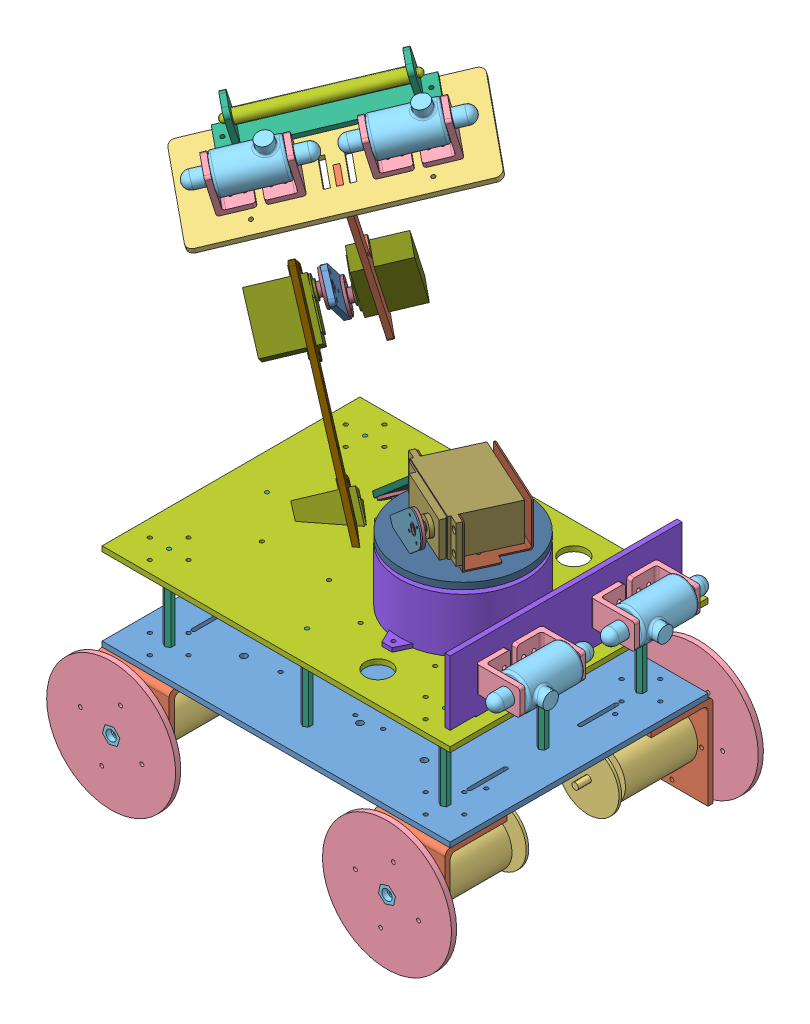
SolidWorks assembly robot_config5 - Copy (2), configuration Default. Lengths in mm.
Overall size (396.29 402.14 292.25).
62 component instances, 26 part files, 158 mates.
Components (placement in the parent):
- base_odroid_down_fix-1: base_odroid_down_fix [Default] at (39.4639 122.941 229.7749) x (1 0 0) z (0 -1 0) size (270 200 4)
- link_motor_1_port-1: link_motor_1_port [Default] at (221.3654 106.3394 287.3354) x (0 0 -1) z (1 0 0) size (48 72 56)
- motor_dc_NISCA-1: motor_dc_NISCA [Default] at (244.2642 39.7289 313.6416) x (0 -1 0) z (0 0 -1) size (54 48 92)
- roda_shaft-1: roda_shaft [Default] at (185.8398 121.6563 330.6416) x (-0.980223 0.197896 0) z (0 0 1) size (100 100 4)
- shaft_adapter_5mm-1: shaft_adapter_5mm [Default] at (248.7954 72.9583 317.6416) x (0.980223 -0.197896 0) z (0 0 1) size (12 13.86 17)
- link_motor_1_port-2: link_motor_1_port [Default] at (221.3654 106.3394 139.9479) x (0 0 1) z (-1 0 0) size (48 72 56)
- motor_dc_NISCA-2: motor_dc_NISCA [Default] at (198.4666 39.7289 113.6416) x (0 -1 0) z (0 0 1) size (54 48 92)
- shaft_adapter_5mm-3: shaft_adapter_5mm [Default] at (200.8263 105.1818 109.6416) x (-0.553843 0.832621 0) z (0 0 -1) size (12 13.86 17)
- roda_shaft-2: roda_shaft [Default] at (229.4077 32.7567 96.6416) x (-0.44415 -0.895953 0) z (0 0 -1) size (100 100 4)
- link_motor_1_port-5: link_motor_1_port [Default] at (7.3654 106.3394 287.3354) x (0 0 -1) z (1 0 0) size (48 72 56)
- motor_dc_NISCA-5: motor_dc_NISCA [Default] at (-15.5334 128.1531 313.6416) x (0 1 0) z (0 0 -1) size (54 48 92)
- roda_shaft-5: roda_shaft [Default] at (-41.8024 67.5996 334.6416) x (-0.956744 0.29093 0) z (0 0 -1) size (100 100 4)
- shaft_adapter_5mm-6: shaft_adapter_5mm [Default] at (33.6165 70.3799 317.6416) x (0.956744 -0.29093 0) z (0 0 1) size (12 13.86 17)
- link_motor_1_port-6: link_motor_1_port [Default] at (7.3654 106.3394 139.9479) x (0 0 1) z (-1 0 0) size (48 72 56)
- motor_dc_NISCA-6: motor_dc_NISCA [Default] at (-15.5334 39.7289 113.6416) x (0 -1 0) z (0 0 1) size (54 48 92)
- roda_shaft-6: roda_shaft [Default] at (45.258 48.6046 96.6416) x (0.202799 -0.97922 0) z (0 0 -1) size (100 100 4)
- shaft_adapter_5mm-7: shaft_adapter_5mm [Default] at (36.6325 79.8838 109.6416) x (0.949429 -0.313981 0) z (0 0 -1) size (12 13.86 17)
- spacer_6cm-2: spacer_6cm [Default] at (221.7099 182.941 288.7798) x (0.5 0 -0.866025) z (0 -1 0) size (6 6.93 68)
- spacer_6cm-3: spacer_6cm [Default] at (114.7099 182.941 288.7798) x (0.5 0 -0.866025) z (0 -1 0) size (6 6.93 68)
- spacer_6cm-4: spacer_6cm [Default] at (7.7099 182.941 288.7798) x (0.5 0 -0.866025) z (0 -1 0) size (6 6.93 68)
- spacer_6cm-5: spacer_6cm [Default] at (221.7099 182.941 212.7798) x (0.5 0 -0.866025) z (0 -1 0) size (6 6.93 68)
- spacer_6cm-7: spacer_6cm [Default] at (7.7099 182.941 212.7798) x (0.5 0 -0.866025) z (0 -1 0) size (6 6.93 68)
- spacer_6cm-8: spacer_6cm [Default] at (221.7099 182.941 136.7798) x (0.5 0 -0.866025) z (0 -1 0) size (6 6.93 68)
- spacer_6cm-9: spacer_6cm [Default] at (114.7099 182.941 136.7798) x (0.5 0 -0.866025) z (0 -1 0) size (6 6.93 68)
- spacer_6cm-10: spacer_6cm [Default] at (7.7099 182.941 136.7798) x (0.5 0 -0.866025) z (0 -1 0) size (6 6.93 68)
- base_odroid_up_fix-1: base_odroid_up_fix [Default] at (186.1287 186.941 197.5083) x (-1 0 0) z (0 -1 0) size (270 200 4)
- base_arm-1: base_arm [Default] at (159.3654 194.0898 219.4289) x (0 0 1) z (-1 0 0) size (118.01 42 118.01)
- servo_hs422-1: servo_hs422 [Default] at (169.6524 210.6756 203.7356) x (0 0 1) z (-1 0 0) size (19.81 42.14 58.23)
- link1_arm-1: link1_arm [Default] at (135.1247 232.0663 202.5671) x (-0.909573 0 -0.415545) z (0 1 0) size (98 98 12)
- bracket_servo_hs755-1: bracket_servo_hs755 [Default] at (176.7251 266.4802 264.6833) x (-0.415545 0 0.909573) z (-0.909573 0 -0.415545) size (44 34 74)
- servo_hs755-1: servo_hs755 [Default] at (178.9415 211.9363 195.0997) x (0 -1 0) z (-0.415545 0 0.909573) size (29 74 56.99)
- servo_horn_general-1: servo_horn_general [Default] at (190.0175 289.5121 265.0144) x (0.696773 0.642788 0.318326) z (0.415545 0 -0.909573) size (24 24 6)
- link2_ubracket-2: link2_ubracket [Default] at (158.0154 222.8169 200.5977) x (0.415545 0 -0.909573) z (-0.584662 0.766044 -0.267107) size (66 59 24)
- link2_fix-2: link2_fix [Default] at (114.6727 188.4592 181.7629) x (0.584662 -0.766044 0.267107) z (-0.415545 0 0.909573) size (45.14 89 24)
- servo_horn_general-2: servo_horn_general [Default] at (103.8923 228.8235 186.5401) x (0.696773 0.642788 0.318326) z (0.584662 -0.766044 0.267107) size (24 24 6)
- servo_hs645-2: servo_hs645 [Default] at (126.0021 193.6332 203.2764) x (0.504037 0.60098 0.620298) z (-0.584662 0.766044 -0.267107) size (53.34 19.56 42.35)
- bracket_servo_645-2: bracket_servo_645 [Default] at (74.1941 209.6602 189.4229) x (-0.584662 0.766044 -0.267107) z (-0.504037 -0.60098 -0.620298) size (34 24 57)
- servo_horn_general-3: servo_horn_general [Default] at (55.5106 142.3644 163.5271) x (-0.33554 -0.778769 -0.53003) z (-0.635702 -0.228033 0.737485) size (24 24 6)
- servo_hs645-3: servo_hs645 [Default] at (65.2626 126.9078 227.2968) x (0.612579 -0.730355 0.302206) z (0.635702 0.228033 -0.737485) size (53.34 19.56 42.35)
- link4_fix-1: link4_fix [Default] at (-61.5231 313.2532 136.8813) x (-0.612579 0.730355 -0.302206) z (0.635702 0.228033 -0.737485) size (176.25 35 4)
- servo_hs645-4: servo_hs645 [Default] at (-62.0861 309.963 174.1253) x (-0.612579 0.730355 -0.302206) z (0.635702 0.228033 -0.737485) size (53.34 19.56 42.35)
- link5_fix-1: link5_fix [Default] at (-52.3441 298.5328 118.8456) x (-0.612579 0.730355 -0.302206) z (0.635702 0.228033 -0.737485) size (24 90 4)
- servo_horn_general-4: servo_horn_general [Default] at (10.0609 307.9733 175.5569) x (0.469713 0.643881 0.603976) z (-0.635702 -0.228033 0.737485) size (24 24 6)
- servo_horn_general-5: servo_horn_general [Default] at (-62.2618 206.2599 76.3417) x (-0.469713 -0.643881 -0.603976) z (0.635702 0.228033 -0.737485) size (24 24 6)
- servo_hs645-5: servo_hs645 [Default] at (-5.9799 205.0814 64.3486) x (-0.048645 -0.941639 -0.33309) z (-0.635702 -0.228033 0.737485) size (53.34 19.56 42.35)
- link6_eff-1: link6_eff [Default] at (-35.7215 211.1303 71.6661) x (-0.048645 -0.941639 -0.33309) z (-0.635702 -0.228033 0.737485) size (140.63 35 4)
- base_link_effector_fix-2: base_link_effector_fix [Default] at (-1.9069 349.6133 142.6833) x (-0.635702 -0.228033 0.737485) z (0.048645 0.941639 0.33309) size (180 80 4)
- base_webcam_fix1-2: base_webcam_fix1 [Default] at (41.365 368.6316 94.6083) x (-0.635702 -0.228033 0.737485) z (-0.7704 0.247621 -0.587509) size (23 34 20)
- base_webcam_fix1-3: base_webcam_fix1 [Default] at (-6.4638 361.9543 120.4699) x (0.635702 0.228033 -0.737485) z (0.7704 -0.247621 0.587509) size (23 34 20)
- base_webcam_fix1-4: base_webcam_fix1 [Default] at (-15.2125 348.3366 160.2445) x (-0.635702 -0.228033 0.737485) z (-0.7704 0.247621 -0.587509) size (23 34 20)
- base_webcam_fix1-5: base_webcam_fix1 [Default] at (-63.0413 341.6594 186.106) x (0.635702 0.228033 -0.737485) z (0.7704 -0.247621 0.587509) size (23 34 20)
- webcam_sturdy-3: webcam_sturdy [Default] at (2.21 382.0065 134.5684) x (-0.635702 -0.228033 0.737485) z (0.048645 0.941639 0.33309) size (79 27 33.5)
- webcam_sturdy-4: webcam_sturdy [Default] at (-54.3675 361.7116 200.2045) x (-0.635702 -0.228033 0.737485) z (0.048645 0.941639 0.33309) size (79 27 33.5)
- base_GM-1: base_GM [Default] at (-59.9622 361.6513 153.8993) x (-0.635702 -0.228033 0.737485) z (-0.7704 0.247621 -0.587509) size (128 34 20)
- tabung_GM-1: tabung_GM [Default] at (-109.1173 363.7111 126.0884) x (-0.762485 0.036461 -0.645978) z (0.635702 0.228033 -0.737485) size (10 10 116)
- base_webam_base-2: base_webam_base [Default] at (235.3654 219.0582 216.3423) x (0 0 -1) z (1 0 0) size (180 55 4)
- base_webcam_fix1-7: base_webcam_fix1 [Default] at (239.3654 202.941 143.6416) x (0 0 1) z (0 1 0) size (23 34 20)
- base_webcam_fix1-8: base_webcam_fix1 [Default] at (239.3654 222.941 194.6416) x (0 0 -1) z (0 -1 0) size (23 34 20)
- base_webcam_fix1-9: base_webcam_fix1 [Default] at (239.3654 222.941 283.6416) x (0 0 -1) z (0 -1 0) size (23 34 20)
- base_webcam_fix1-10: base_webcam_fix1 [Default] at (239.3654 202.941 232.6416) x (0 0 1) z (0 1 0) size (23 34 20)
- webcam_sturdy-5: webcam_sturdy [Default] at (263.3654 212.941 143.3307) x (0 0 -1) z (1 0 0) size (79 27 33.5)
- webcam_sturdy-6: webcam_sturdy [Default] at (263.3654 212.941 232.3307) x (0 0 -1) z (1 0 0) size (79 27 33.5)
Mates (geometry in assembly coordinates):
- Coincident1: coincident anti-aligned: plane of link_motor_1_port-1 through (193.3654 46.941 313.6416) normal (0 0 -1); plane of motor_dc_NISCA-1 through (221.3654 83.941 313.6416) normal (0 0 1)
- Concentric1: concentric aligned: cylinder of link_motor_1_port-1 through (221.3654 83.941 317.6416) axis (0 0 -1) radius 9.5; cylinder of motor_dc_NISCA-1 through (221.3654 83.941 317.6416) axis (0 0 -1) radius 9
- Concentric2: concentric anti-aligned: cylinder of link_motor_1_port-1 through (221.3654 106.941 317.6416) axis (0 0 -1) radius 1.5; cylinder of motor_dc_NISCA-1 through (221.3654 106.941 311.6416) axis (0 0 1) radius 1.5
- Coincident2: coincident anti-aligned: plane of motor_dc_NISCA-1 through (244.2642 39.7289 317.6416) normal (0 0 1); plane of shaft_adapter_5mm-1 through (221.3654 83.941 317.6416) normal (0 0 -1)
- Concentric4: concentric aligned: cylinder of motor_dc_NISCA-1 through (221.3654 83.941 330.6416) axis (0 0 -1) radius 2.5; cylinder of shaft_adapter_5mm-1 through (221.3654 83.941 330.6416) axis (0 0 -1) radius 2.5
- Coincident3: coincident anti-aligned: plane of roda_shaft-1 through (222.7365 90.7322 322.6416) normal (0.318728 -0.947846 0); plane of shaft_adapter_5mm-1 through (222.7365 90.7322 334.6416) normal (-0.318728 0.947846 0)
- Coincident4: coincident aligned: plane of roda_shaft-1 through (221.3654 83.941 334.6416) normal (0 0 1); plane of shaft_adapter_5mm-1 through (248.7954 72.9583 334.6416) normal (0 0 1)
- Coincident7: coincident anti-aligned: plane of roda_shaft-1 through (214.7985 81.7328 322.6416) normal (0.661495 0.74995 0); plane of shaft_adapter_5mm-1 through (214.7985 81.7328 334.6416) normal (-0.661495 -0.74995 0)
- Coincident8: coincident anti-aligned: plane of link_motor_1_port-2 through (249.3654 46.941 113.6416) normal (0 0 1); plane of motor_dc_NISCA-2 through (221.3654 83.941 113.6416) normal (0 0 -1)
- Concentric5: concentric aligned: cylinder of link_motor_1_port-2 through (221.3654 83.941 109.6416) axis (0 0 1) radius 9.5; cylinder of motor_dc_NISCA-2 through (221.3654 83.941 109.6416) axis (0 0 1) radius 9
- Concentric7: concentric anti-aligned: cylinder of link_motor_1_port-2 through (221.3654 106.941 109.6416) axis (0 0 1) radius 1.5; cylinder of motor_dc_NISCA-2 through (221.3654 106.941 115.6416) axis (0 0 -1) radius 1.5
- Coincident9: coincident anti-aligned: plane of base_odroid_down_fix-1 through (39.4639 118.941 229.7749) normal (0 -1 0); plane of link_motor_1_port-1 through (193.3654 118.941 269.6416) normal (0 1 0)
- Concentric8: concentric anti-aligned: cylinder of base_odroid_down_fix-1 through (206.3654 118.941 289.6416) axis (0 1 0) radius 1.5; cylinder of link_motor_1_port-1 through (206.3654 118.941 289.6416) axis (0 -1 0) radius 1.5
- Concentric9: concentric anti-aligned: cylinder of base_odroid_down_fix-1 through (236.3654 118.941 289.6416) axis (0 1 0) radius 1.5; cylinder of link_motor_1_port-1 through (236.3654 118.941 289.6416) axis (0 -1 0) radius 1.5
- Coincident11: coincident aligned: plane of shaft_adapter_5mm-3 through (200.8263 105.1818 92.6416) normal (0 0 -1); plane of roda_shaft-2 through (221.3654 83.941 92.6416) normal (0 0 -1)
- Coincident12: coincident anti-aligned: plane of shaft_adapter_5mm-3 through (220.9266 90.8553 92.6416) normal (0.44415 0.895953 0); plane of roda_shaft-2 through (220.9266 90.8553 104.6416) normal (-0.44415 -0.895953 0)
- Coincident13: coincident anti-aligned: plane of shaft_adapter_5mm-3 through (215.5968 80.1039 92.6416) normal (-0.997993 -0.063332 0); plane of roda_shaft-2 through (215.5968 80.1039 104.6416) normal (0.997993 0.063332 0)
- Coincident14: coincident anti-aligned: plane of motor_dc_NISCA-2 through (198.4666 39.7289 109.6416) normal (0 0 -1); plane of shaft_adapter_5mm-3 through (221.3654 83.941 109.6416) normal (0 0 1)
- Concentric10: concentric aligned: cylinder of motor_dc_NISCA-2 through (221.3654 83.941 96.6416) axis (0 0 1) radius 2.5; cylinder of shaft_adapter_5mm-3 through (221.3654 83.941 96.6416) axis (0 0 1) radius 2.5
- Coincident15: coincident anti-aligned: plane of base_odroid_down_fix-1 through (39.4639 118.941 229.7749) normal (0 -1 0); plane of link_motor_1_port-2 through (249.3654 118.941 157.6416) normal (0 1 0)
- Concentric11: concentric anti-aligned: cylinder of base_odroid_down_fix-1 through (206.3654 118.941 137.6416) axis (0 1 0) radius 1.5; cylinder of link_motor_1_port-2 through (206.3654 118.941 137.6416) axis (0 -1 0) radius 1.5
- Concentric12: concentric anti-aligned: cylinder of base_odroid_down_fix-1 through (236.3654 118.941 137.6416) axis (0 1 0) radius 1.5; cylinder of link_motor_1_port-2 through (236.3654 118.941 137.6416) axis (0 -1 0) radius 1.5
- Coincident16: coincident anti-aligned: plane of link_motor_1_port-5 through (-20.6346 46.941 313.6416) normal (0 0 -1); plane of motor_dc_NISCA-5 through (7.3654 83.941 313.6416) normal (0 0 1)
- Concentric13: concentric aligned: cylinder of link_motor_1_port-5 through (7.3654 83.941 317.6416) axis (0 0 -1) radius 9.5; cylinder of motor_dc_NISCA-5 through (7.3654 83.941 317.6416) axis (0 0 -1) radius 9
- Concentric14: concentric anti-aligned: cylinder of link_motor_1_port-5 through (7.3654 106.941 317.6416) axis (0 0 -1) radius 1.5; cylinder of motor_dc_NISCA-5 through (7.3654 106.941 311.6416) axis (0 0 1) radius 1.5
- Concentric16: concentric aligned: cylinder of motor_dc_NISCA-5 through (7.3654 83.941 330.6416) axis (0 0 -1) radius 2.5; cylinder of shaft_adapter_5mm-6 through (7.3654 83.941 330.6416) axis (0 0 -1) radius 2.5
- Coincident17: coincident anti-aligned: plane of motor_dc_NISCA-5 through (-15.5334 128.1531 317.6416) normal (0 0 1); plane of shaft_adapter_5mm-6 through (7.3654 83.941 317.6416) normal (0 0 -1)
- Coincident18: coincident anti-aligned: plane of roda_shaft-5 through (2.6327 89.0009 342.6416) normal (0.226419 -0.97403 0); plane of shaft_adapter_5mm-6 through (9.381 90.5695 334.6416) normal (-0.226419 0.97403 0)
- Coincident19: coincident aligned: plane of roda_shaft-5 through (7.3654 83.941 334.6416) normal (0 0 1); plane of shaft_adapter_5mm-6 through (33.6165 70.3799 334.6416) normal (0 0 1)
- Coincident20: coincident anti-aligned: plane of roda_shaft-5 through (14.1137 85.5097 342.6416) normal (-0.956744 0.29093 0); plane of shaft_adapter_5mm-6 through (12.098 78.8812 334.6416) normal (0.956744 -0.29093 0)
- Coincident21: coincident anti-aligned: plane of base_odroid_down_fix-1 through (39.4639 118.941 229.7749) normal (0 -1 0); plane of link_motor_1_port-5 through (-20.6346 118.941 269.6416) normal (0 1 0)
- Concentric17: concentric anti-aligned: cylinder of base_odroid_down_fix-1 through (-7.6346 118.941 289.6416) axis (0 1 0) radius 1.5; cylinder of link_motor_1_port-5 through (-7.6346 118.941 289.6416) axis (0 -1 0) radius 1.5
- Concentric18: concentric anti-aligned: cylinder of base_odroid_down_fix-1 through (22.3654 118.941 289.6416) axis (0 1 0) radius 1.5; cylinder of link_motor_1_port-5 through (22.3654 118.941 289.6416) axis (0 -1 0) radius 1.5
- Coincident22: coincident anti-aligned: plane of link_motor_1_port-6 through (35.3654 46.941 113.6416) normal (0 0 1); plane of motor_dc_NISCA-6 through (7.3654 83.941 113.6416) normal (0 0 -1)
- Concentric19: concentric aligned: cylinder of link_motor_1_port-6 through (7.3654 83.941 109.6416) axis (0 0 1) radius 9.5; cylinder of motor_dc_NISCA-6 through (7.3654 83.941 109.6416) axis (0 0 1) radius 9
- Concentric20: concentric anti-aligned: cylinder of link_motor_1_port-6 through (7.3654 106.941 109.6416) axis (0 0 1) radius 1.5; cylinder of motor_dc_NISCA-6 through (7.3654 106.941 115.6416) axis (0 0 -1) radius 1.5
- Concentric21: concentric aligned: cylinder of motor_dc_NISCA-6 through (7.3654 83.941 96.6416) axis (0 0 1) radius 2.5; cylinder of shaft_adapter_5mm-7 through (7.3654 83.941 96.6416) axis (0 0 1) radius 2.5
- Coincident23: coincident anti-aligned: plane of motor_dc_NISCA-6 through (-15.5334 39.7289 109.6416) normal (0 0 -1); plane of shaft_adapter_5mm-7 through (7.3654 83.941 109.6416) normal (0 0 1)
- Coincident24: coincident aligned: plane of roda_shaft-6 through (7.3654 83.941 92.6416) normal (0 0 -1); plane of shaft_adapter_5mm-7 through (36.6325 79.8838 92.6416) normal (0 0 -1)
- Coincident25: coincident anti-aligned: plane of roda_shaft-6 through (2.7565 89.1138 104.6416) normal (0.202799 -0.97922 0); plane of shaft_adapter_5mm-7 through (2.7565 89.1138 92.6416) normal (-0.202799 0.97922 0)
- Coincident26: coincident anti-aligned: plane of roda_shaft-6 through (5.1901 77.3632 104.6416) normal (0.74663 0.665239 0); plane of shaft_adapter_5mm-7 through (5.1901 77.3632 92.6416) normal (-0.74663 -0.665239 0)
- Coincident27: coincident anti-aligned: plane of base_odroid_down_fix-1 through (39.4639 118.941 229.7749) normal (0 -1 0); plane of link_motor_1_port-6 through (35.3654 118.941 157.6416) normal (0 1 0)
- Concentric22: concentric anti-aligned: cylinder of base_odroid_down_fix-1 through (-7.6346 118.941 137.6416) axis (0 1 0) radius 1.5; cylinder of link_motor_1_port-6 through (-7.6346 118.941 137.6416) axis (0 -1 0) radius 1.5
- Concentric23: concentric anti-aligned: cylinder of base_odroid_down_fix-1 through (22.3654 118.941 137.6416) axis (0 1 0) radius 1.5; cylinder of link_motor_1_port-6 through (22.3654 118.941 137.6416) axis (0 -1 0) radius 1.5
- Concentric24: concentric aligned: cylinder of base_odroid_down_fix-1 through (221.3654 118.941 289.6416) axis (0 1 0) radius 1.5; cylinder of spacer_6cm-2 through (221.3654 118.941 289.6416) axis (0 1 0) radius 1.5
- Coincident28: coincident anti-aligned: plane of base_odroid_down_fix-1 through (39.4639 122.941 229.7749) normal (0 1 0); plane of spacer_6cm-2 through (221.7099 122.941 288.7798) normal (0 -1 0)
- Parallel2: parallel aligned: plane of base_odroid_down_fix-1 through (249.3654 118.941 229.7749) normal (1 0 0); plane of spacer_6cm-2 through (224.3654 122.941 287.9096) normal (1 0 0)
- Concentric25: concentric anti-aligned: cylinder of spacer_6cm-2 through (221.3654 186.941 289.6416) axis (0 -1 0) radius 1.5; cylinder of base_odroid_up_fix-1 through (221.3654 182.941 289.6416) axis (0 1 0) radius 1.5
- Concentric26: concentric anti-aligned: cylinder of spacer_6cm-7 through (7.3654 186.941 213.6416) axis (0 -1 0) radius 1.5; cylinder of base_odroid_up_fix-1 through (7.3654 182.941 213.6416) axis (0 1 0) radius 1.5
- Coincident29: coincident anti-aligned: plane of spacer_6cm-2 through (221.7099 182.941 288.7798) normal (0 1 0); plane of base_odroid_up_fix-1 through (186.1287 182.941 197.5083) normal (0 -1 0)
- Coincident31: coincident anti-aligned: plane of base_arm-1 through (159.3654 225.941 213.6416) normal (0 -1 0); plane of servo_hs422-1 through (169.6524 225.941 203.7356) normal (0 1 0)
- Parallel3: parallel aligned: plane of base_odroid_up_fix-1 through (249.3654 182.941 197.5083) normal (1 0 0); plane of servo_hs422-1 through (189.5914 210.6756 223.5476) normal (1 0 0)
- Coincident33: coincident anti-aligned: plane of base_odroid_up_fix-1 through (186.1287 186.941 197.5083) normal (0 1 0); plane of base_arm-1 through (159.3654 186.941 259.6416) normal (0 -1 0)
- Concentric28: concentric anti-aligned: cylinder of base_odroid_up_fix-1 through (213.3654 182.941 213.6416) axis (0 1 0) radius 1.5; cylinder of base_arm-1 through (213.3654 189.941 213.6416) axis (0 -1 0) radius 1.5
- Concentric29: concentric anti-aligned: plane of base_odroid_up_fix-1; plane of base_arm-1
- Parallel5: parallel aligned: plane of base_odroid_up_fix-1 through (186.1287 182.941 113.6416) normal (0 0 -1); plane of servo_hs422-1 through (169.6524 210.6756 203.7356) normal (0 0 -1)
- Concentric30: concentric aligned: cylinder of base_arm-1 through (159.3654 225.941 213.6416) axis (0 1 0) radius 5.4623; cylinder of servo_hs422-1 through (159.3654 202.0734 213.6416) axis (0 1 0) radius 6.4897
- Concentric31: concentric aligned: cylinder of servo_hs422-1 through (159.3654 212.8107 213.6416) axis (0 1 0) radius 2.8131; cylinder of link1_arm-1 through (159.3654 228.0663 213.6416) axis (0 1 0) radius 3
- Coincident36: coincident anti-aligned: plane of servo_hs422-1 through (169.6524 232.0663 223.5476) normal (0 1 0); plane of link1_arm-1 through (159.3654 232.0663 213.6416) normal (0 -1 0)
- Concentric32: concentric aligned: cylinder of link1_arm-1 through (159.3654 240.0663 213.6416) axis (0 -1 0) radius 4; cylinder of bracket_servo_hs755-1 through (159.3654 238.0663 213.6416) axis (0 -1 0) radius 4
- Coincident38: coincident anti-aligned: plane of link1_arm-1 through (159.3654 237.0663 213.6416) normal (0 1 0); plane of bracket_servo_hs755-1 through (138.1775 237.0663 170.9793) normal (0 -1 0)
- Concentric33: concentric anti-aligned: cylinder of link1_arm-1 through (152.0888 232.0663 210.3173) axis (0 1 0) radius 1.5; cylinder of bracket_servo_hs755-1 through (152.0888 238.0663 210.3173) axis (0 -1 0) radius 1.5
- Coincident40: coincident anti-aligned: plane of bracket_servo_hs755-1 through (119.8936 237.0663 211.0005) normal (-0.415545 0 0.909573); plane of servo_hs755-1 through (162.7353 211.9363 230.573) normal (0.415545 0 -0.909573)
- Concentric36: concentric aligned: cylinder of bracket_servo_hs755-1 through (123.0378 248.5663 211.3375) axis (-0.415545 0 0.909573) radius 1.5; cylinder of servo_hs755-1 through (122.6223 248.5663 212.2471) axis (-0.415545 0 0.909573) radius 2.5
- Concentric37: concentric aligned: cylinder of bracket_servo_hs755-1 through (184.8888 264.5663 239.5946) axis (-0.415545 0 0.909573) radius 1.5; cylinder of servo_hs755-1 through (184.4732 264.5663 240.5042) axis (-0.415545 0 0.909573) radius 2.5
- Concentric39: concentric anti-aligned: cylinder of servo_hs755-1 through (160.1705 257.0663 249.1798) axis (0.415545 0 -0.909573) radius 3; cylinder of servo_horn_general-1 through (161.4171 257.0663 246.4511) axis (-0.415545 0 0.909573) radius 3
- Coincident41: coincident anti-aligned: plane of servo_hs755-1 through (160.1705 257.0663 249.1798) normal (-0.415545 0 0.909573); plane of servo_horn_general-1 through (160.1705 257.0663 249.1798) normal (0.415545 0 -0.909573)
- Concentric40: concentric anti-aligned: cylinder of servo_horn_general-1 through (158.9238 257.0663 251.9085) axis (0.415545 0 -0.909573) radius 4; cylinder of link2_ubracket-2 through (159.3394 257.0663 250.9989) axis (-0.415545 0 0.909573) radius 4
- Coincident42: coincident anti-aligned: plane of servo_horn_general-1 through (159.3394 257.0663 250.9989) normal (-0.415545 0 0.909573); plane of link2_ubracket-2 through (126.4233 242.3654 235.961) normal (0.415545 0 -0.909573)
- Concentric41: concentric aligned: cylinder of servo_horn_general-1 through (164.8478 250.9379 251.3166) axis (-0.415545 0 0.909573) radius 0.5; cylinder of link2_ubracket-2 through (164.0167 250.9379 253.1358) axis (-0.415545 0 0.909573) radius 1
- Coincident46: coincident anti-aligned: plane of link2_ubracket-2 through (123.0716 236.0478 225.179) normal (-0.696773 -0.642788 -0.318326); plane of link2_fix-2 through (139.7208 220.767 219.5923) normal (0.696773 0.642788 0.318326)
- Concentric45: concentric anti-aligned: cylinder of link2_ubracket-2 through (140.7574 227.4981 206.8729) axis (-0.696773 -0.642788 -0.318326) radius 4; cylinder of link2_fix-2 through (137.2735 224.2841 205.2812) axis (0.696773 0.642788 0.318326) radius 4
- Concentric46: concentric anti-aligned: cylinder of link2_ubracket-2 through (144.0818 227.4981 199.5963) axis (-0.696773 -0.642788 -0.318326) radius 1; cylinder of link2_fix-2 through (140.5979 224.2841 198.0047) axis (0.696773 0.642788 0.318326) radius 1.5
- Coincident47: coincident anti-aligned: plane of servo_horn_general-2 through (71.2079 197.2778 175.0987) normal (0.584662 -0.766044 0.267107); plane of servo_hs645-2 through (71.2079 197.2778 175.0987) normal (-0.584662 0.766044 -0.267107)
- Concentric48: concentric anti-aligned: cylinder of servo_horn_general-2 through (72.9619 194.9797 175.9) axis (-0.584662 0.766044 -0.267107) radius 3; cylinder of servo_hs645-2 through (71.2079 197.2778 175.0987) axis (0.584662 -0.766044 0.267107) radius 2.9972
- Coincident48: coincident anti-aligned: plane of link2_fix-2 through (83.6824 215.9968 193.9907) normal (0.584662 -0.766044 0.267107); plane of servo_horn_general-2 through (70.0386 198.8099 174.5644) normal (-0.584662 0.766044 -0.267107)
- Concentric49: concentric anti-aligned: cylinder of link2_fix-2 through (70.0386 198.8099 174.5644) axis (-0.584662 0.766044 -0.267107) radius 4; cylinder of servo_horn_general-2 through (69.4539 199.5759 174.2973) axis (0.584662 -0.766044 0.267107) radius 4
- Concentric50: concentric aligned: cylinder of link2_fix-2 through (73.3629 198.8099 167.2879) axis (-0.584662 0.766044 -0.267107) radius 1.5; cylinder of servo_horn_general-2 through (74.5322 197.2778 167.8221) axis (-0.584662 0.766044 -0.267107) radius 0.5
- Coincident50: coincident anti-aligned: plane of servo_hs645-2 through (109.2954 215.5229 195.6438) normal (-0.584662 0.766044 -0.267107); plane of bracket_servo_645-2 through (51.279 160.226 164.0464) normal (0.584662 -0.766044 0.267107)
- Concentric51: concentric aligned: cylinder of servo_hs645-2 through (91.2967 193.5966 184.044) axis (-0.584662 0.766044 -0.267107) radius 2.5019; cylinder of bracket_servo_645-2 through (90.3408 194.8491 183.6073) axis (-0.584662 0.766044 -0.267107) radius 1.5
- Concentric52: concentric aligned: cylinder of servo_hs645-2 through (66.9719 164.5933 154.1084) axis (-0.584662 0.766044 -0.267107) radius 2.5019; cylinder of bracket_servo_645-2 through (66.016 165.8458 153.6717) axis (-0.584662 0.766044 -0.267107) radius 1.5
- Concentric53: concentric aligned: cylinder of bracket_servo_645-2 through (74.021 177.0999 188.8672) axis (-0.635702 -0.228033 0.737485) radius 4; cylinder of servo_horn_general-3 through (74.021 177.0999 188.8672) axis (-0.635702 -0.228033 0.737485) radius 4
- Coincident51: coincident anti-aligned: plane of bracket_servo_645-2 through (67.5985 137.7827 172.53) normal (-0.635702 -0.228033 0.737485); plane of servo_horn_general-3 through (73.3853 176.8719 189.6046) normal (0.635702 0.228033 -0.737485)
- Concentric54: concentric anti-aligned: cylinder of bracket_servo_645-2 through (78.6983 170.9716 191.004) axis (-0.635702 -0.228033 0.737485) radius 1.5; cylinder of servo_horn_general-3 through (76.7912 170.2875 193.2165) axis (0.635702 0.228033 -0.737485) radius 0.5
- Coincident52: coincident anti-aligned: plane of servo_horn_general-3 through (72.1139 176.4158 191.0796) normal (-0.635702 -0.228033 0.737485); plane of servo_hs645-3 through (72.1139 176.4158 191.0796) normal (0.635702 0.228033 -0.737485)
- Concentric55: concentric anti-aligned: cylinder of servo_horn_general-3 through (70.2068 175.7317 193.2921) axis (0.635702 0.228033 -0.737485) radius 3; cylinder of servo_hs645-3 through (72.1139 176.4158 191.0796) axis (-0.635702 -0.228033 0.737485) radius 2.9972
- Concentric61: concentric anti-aligned: cylinder of servo_hs645-4 through (-15.0877 279.7714 147.871) axis (-0.635702 -0.228033 0.737485) radius 2.9972; cylinder of servo_horn_general-4 through (-16.9948 279.0873 150.0834) axis (0.635702 0.228033 -0.737485) radius 3
- Coincident56: coincident anti-aligned: plane of servo_hs645-4 through (-15.0877 279.7714 147.871) normal (0.635702 0.228033 -0.737485); plane of servo_horn_general-4 through (-15.0877 279.7714 147.871) normal (-0.635702 -0.228033 0.737485)
- Coincident57: coincident anti-aligned: plane of link5_fix-1 through (-52.3441 298.5328 118.8456) normal (-0.635702 -0.228033 0.737485); plane of servo_horn_general-4 through (-13.8163 280.2275 146.396) normal (0.635702 0.228033 -0.737485)
- Concentric62: concentric anti-aligned: cylinder of link5_fix-1 through (-13.8163 280.2275 146.396) axis (0.635702 0.228033 -0.737485) radius 4; cylinder of servo_horn_general-4 through (-13.1806 280.4555 145.6585) axis (-0.635702 -0.228033 0.737485) radius 4
- Concentric63: concentric aligned: cylinder of link5_fix-1 through (-18.7169 286.0703 143.9783) axis (0.635702 0.228033 -0.737485) radius 1.5; cylinder of servo_horn_general-4 through (-19.9883 285.6142 145.4533) axis (0.635702 0.228033 -0.737485) radius 0.5
- Concentric64: concentric anti-aligned: cylinder of servo_horn_general-5 through (-39.096 239.7836 99.8962) axis (-0.635702 -0.228033 0.737485) radius 3; cylinder of servo_hs645-5 through (-41.0031 239.0995 102.1086) axis (0.635702 0.228033 -0.737485) radius 2.9972
- Coincident58: coincident anti-aligned: plane of servo_horn_general-5 through (-41.0031 239.0995 102.1086) normal (0.635702 0.228033 -0.737485); plane of servo_hs645-5 through (-41.0031 239.0995 102.1086) normal (-0.635702 -0.228033 0.737485)
- Coincident59: coincident anti-aligned: plane of link5_fix-1 through (-49.8013 299.445 115.8957) normal (0.635702 0.228033 -0.737485); plane of servo_horn_general-5 through (-42.2745 238.6435 103.5836) normal (-0.635702 -0.228033 0.737485)
- Concentric65: concentric aligned: cylinder of link5_fix-1 through (-44.8173 237.7313 106.5335) axis (0.635702 0.228033 -0.737485) radius 4; cylinder of servo_horn_general-5 through (-42.9102 238.4154 104.3211) axis (0.635702 0.228033 -0.737485) radius 4
- Concentric66: concentric anti-aligned: cylinder of link5_fix-1 through (-39.9167 231.8885 108.9512) axis (0.635702 0.228033 -0.737485) radius 1.5; cylinder of servo_horn_general-5 through (-36.1025 233.2567 104.5263) axis (-0.635702 -0.228033 0.737485) radius 0.5
- Coincident60: coincident anti-aligned: plane of servo_hs645-5 through (-23.0956 198.9418 84.2046) normal (0.635702 0.228033 -0.737485); plane of link6_eff-1 through (-38.2643 210.2182 74.6161) normal (-0.635702 -0.228033 0.737485)
- Concentric67: concentric aligned: cylinder of servo_hs645-5 through (-34.5979 231.4844 82.2856) axis (-0.635702 -0.228033 0.737485) radius 2.5019; cylinder of link6_eff-1 through (-33.0239 232.049 80.4596) axis (-0.635702 -0.228033 0.737485) radius 1.5
- Concentric68: concentric aligned: cylinder of servo_hs645-5 through (-32.2503 276.9279 98.3605) axis (-0.635702 -0.228033 0.737485) radius 2.5019; cylinder of link6_eff-1 through (-30.6763 277.4925 96.5345) axis (-0.635702 -0.228033 0.737485) radius 1.5
- Coincident61: coincident aligned: plane of link6_eff-1 through (-30.4956 360.599 127.8109) normal (0.048645 0.941639 0.33309); plane of base_link_effector_fix-2 through (-1.7123 353.3799 144.0156) normal (0.048645 0.941639 0.33309)
- Coincident62: coincident anti-aligned: plane of link6_eff-1 through (-38.2643 210.2182 74.6161) normal (-0.635702 -0.228033 0.737485); plane of base_link_effector_fix-2 through (-5.7558 348.8181 145.4936) normal (0.635702 0.228033 -0.737485)
- Coincident63: coincident anti-aligned: plane of link6_eff-1 through (-13.3299 202.2038 93.6311) normal (0.7704 -0.247621 0.587509); plane of base_link_effector_fix-2 through (-3.213 349.7302 142.5437) normal (-0.7704 0.247621 -0.587509)
- Coincident72: coincident anti-aligned: plane of base_link_effector_fix-2 through (-1.7123 353.3799 144.0156) normal (0.048645 0.941639 0.33309); plane of base_webcam_fix1-2 through (25.957 373.584 82.8582) normal (-0.048645 -0.941639 -0.33309)
- Concentric71: concentric anti-aligned: cylinder of base_link_effector_fix-2 through (22.2183 367.0032 102.008) axis (-0.048645 -0.941639 -0.33309) radius 1.5; cylinder of base_webcam_fix1-2 through (22.2183 367.0032 102.008) axis (0.048645 0.941639 0.33309) radius 1.5
- Concentric72: concentric anti-aligned: cylinder of base_link_effector_fix-2 through (27.304 368.8274 96.1081) axis (-0.048645 -0.941639 -0.33309) radius 1.5; cylinder of base_webcam_fix1-2 through (27.304 368.8274 96.1081) axis (0.048645 0.941639 0.33309) radius 1.5
- Coincident73: coincident anti-aligned: plane of base_link_effector_fix-2 through (-1.7123 353.3799 144.0156) normal (0.048645 0.941639 0.33309); plane of base_webcam_fix1-3 through (8.9442 357.0019 132.2201) normal (-0.048645 -0.941639 -0.33309)
- Concentric73: concentric anti-aligned: cylinder of base_link_effector_fix-2 through (7.5972 361.7584 118.9701) axis (-0.048645 -0.941639 -0.33309) radius 1.5; cylinder of base_webcam_fix1-3 through (7.5972 361.7584 118.9701) axis (0.048645 0.941639 0.33309) radius 1.5
- Concentric74: concentric anti-aligned: cylinder of base_link_effector_fix-2 through (12.6828 363.5827 113.0702) axis (-0.048645 -0.941639 -0.33309) radius 1.5; cylinder of base_webcam_fix1-3 through (12.6828 363.5827 113.0702) axis (0.048645 0.941639 0.33309) radius 1.5
- Coincident74: coincident anti-aligned: plane of base_link_effector_fix-2 through (-1.7123 353.3799 144.0156) normal (0.048645 0.941639 0.33309); plane of base_webcam_fix1-4 through (-30.6205 353.289 148.4943) normal (-0.048645 -0.941639 -0.33309)
- Concentric75: concentric anti-aligned: cylinder of base_link_effector_fix-2 through (-34.3592 346.7082 167.6441) axis (-0.048645 -0.941639 -0.33309) radius 1.5; cylinder of base_webcam_fix1-4 through (-34.3592 346.7082 167.6441) axis (0.048645 0.941639 0.33309) radius 1.5
- Concentric76: concentric anti-aligned: cylinder of base_link_effector_fix-2 through (-29.2735 348.5325 161.7442) axis (-0.048645 -0.941639 -0.33309) radius 1.5; cylinder of base_webcam_fix1-4 through (-29.2735 348.5325 161.7442) axis (0.048645 0.941639 0.33309) radius 1.5
- Coincident75: coincident anti-aligned: plane of base_link_effector_fix-2 through (-1.7123 353.3799 144.0156) normal (0.048645 0.941639 0.33309); plane of base_webcam_fix1-5 through (-47.6333 336.7069 197.8562) normal (-0.048645 -0.941639 -0.33309)
- Concentric77: concentric anti-aligned: cylinder of base_link_effector_fix-2 through (-43.8947 343.2877 178.7064) axis (-0.048645 -0.941639 -0.33309) radius 1.5; cylinder of base_webcam_fix1-5 through (-43.8947 343.2877 178.7064) axis (0.048645 0.941639 0.33309) radius 1.5
- Concentric78: concentric anti-aligned: cylinder of base_link_effector_fix-2 through (-48.9803 341.4635 184.6063) axis (-0.048645 -0.941639 -0.33309) radius 1.5; cylinder of base_webcam_fix1-5 through (-48.9803 341.4635 184.6063) axis (0.048645 0.941639 0.33309) radius 1.5
- Concentric79: concentric anti-aligned: cylinder of base_webcam_fix1-2 through (32.2857 392.795 99.6773) axis (0.635702 0.228033 -0.737485) radius 6; cylinder of webcam_sturdy-3 through (43.7283 396.8996 86.4026) axis (-0.635702 -0.228033 0.737485) radius 6
- Coincident78: coincident anti-aligned: plane of base_webcam_fix1-3 through (11.6816 361.6806 130.6025) normal (0.635702 0.228033 -0.737485); plane of webcam_sturdy-3 through (4.9505 382.9896 131.3892) normal (-0.635702 -0.228033 0.737485)
- Parallel8: parallel aligned: plane of base_link_effector_fix-2 through (-1.7123 353.3799 144.0156) normal (0.048645 0.941639 0.33309); plane of webcam_sturdy-3 through (26.9015 409.3474 113.714) normal (0.048645 0.941639 0.33309)
- Concentric80: concentric anti-aligned: cylinder of base_webcam_fix1-4 through (-24.2918 372.5 165.3135) axis (0.635702 0.228033 -0.737485) radius 6; cylinder of webcam_sturdy-4 through (-12.8492 376.6046 152.0388) axis (-0.635702 -0.228033 0.737485) radius 6
- Coincident80: coincident anti-aligned: plane of base_webcam_fix1-5 through (-44.8959 341.3856 196.2386) normal (0.635702 0.228033 -0.737485); plane of webcam_sturdy-4 through (-51.627 362.6946 197.0253) normal (-0.635702 -0.228033 0.737485)
- Parallel9: parallel aligned: plane of base_link_effector_fix-2 through (-1.7123 353.3799 144.0156) normal (0.048645 0.941639 0.33309); plane of webcam_sturdy-4 through (-29.676 389.0525 179.3501) normal (0.048645 0.941639 0.33309)
- Coincident82: coincident anti-aligned: plane of base_link_effector_fix-2 through (-1.7123 353.3799 144.0156) normal (0.048645 0.941639 0.33309); plane of base_GM-1 through (-16.1859 380.2117 70.2763) normal (-0.048645 -0.941639 -0.33309)
- Concentric81: concentric anti-aligned: cylinder of base_link_effector_fix-2 through (-80.3162 351.9678 159.4871) axis (-0.048645 -0.941639 -0.33309) radius 1.5; cylinder of base_GM-1 through (-80.3162 351.9678 159.4871) axis (0.048645 0.941639 0.33309) radius 1.5
- Concentric82: concentric anti-aligned: cylinder of base_link_effector_fix-2 through (-5.3034 378.8757 72.4639) axis (-0.048645 -0.941639 -0.33309) radius 1.5; cylinder of base_GM-1 through (-5.3034 378.8757 72.4639) axis (0.048645 0.941639 0.33309) radius 1.5
- Concentric83: concentric anti-aligned: cylinder of base_GM-1 through (-73.6706 371.9112 159.1785) axis (-0.635702 -0.228033 0.737485) radius 3; cylinder of tabung_GM-1 through (-78.7562 370.087 165.0784) axis (0.635702 0.228033 -0.737485) radius 3
- Coincident83: coincident anti-aligned: plane of base_GM-1 through (-17.0747 411.3153 84.5513) normal (-0.635702 -0.228033 0.737485); plane of tabung_GM-1 through (-10.1004 394.7145 85.43) normal (0.635702 0.228033 -0.737485)
- Coincident85: coincident anti-aligned: plane of link4_fix-1 through (-61.5231 313.2532 136.8813) normal (-0.635702 -0.228033 0.737485); plane of servo_hs645-4 through (-43.9209 316.4791 153.0517) normal (0.635702 0.228033 -0.737485)
- Concentric86: concentric aligned: cylinder of link4_fix-1 through (-34.3607 283.3539 151.05) axis (0.635702 0.228033 -0.737485) radius 1.5; cylinder of servo_hs645-4 through (-36.3791 282.6299 153.3916) axis (0.635702 0.228033 -0.737485) radius 2.5019
- Concentric87: concentric aligned: cylinder of link4_fix-1 through (-0.0254 254.6488 171.7709) axis (0.635702 0.228033 -0.737485) radius 1.5; cylinder of servo_hs645-4 through (-2.0437 253.9248 174.1124) axis (0.635702 0.228033 -0.737485) radius 2.5019
- Coincident86: coincident anti-aligned: plane of servo_hs645-3 through (83.4278 133.4238 206.2232) normal (0.635702 0.228033 -0.737485); plane of link4_fix-1 through (-61.5231 313.2532 136.8813) normal (-0.635702 -0.228033 0.737485)
- Concentric88: concentric aligned: cylinder of servo_hs645-3 through (67.0769 159.2832 204.43) axis (0.635702 0.228033 -0.737485) radius 2.5019; cylinder of link4_fix-1 through (69.0953 160.0072 202.0885) axis (0.635702 0.228033 -0.737485) radius 1.5
- Concentric89: concentric aligned: cylinder of servo_hs645-3 through (37.5139 194.5301 189.8455) axis (0.635702 0.228033 -0.737485) radius 2.5019; cylinder of link4_fix-1 through (39.5322 195.2541 187.504) axis (0.635702 0.228033 -0.737485) radius 1.5
- LimitAngle1: limit planar angle = 1.999338 rad anti-aligned: plane of servo_hs755-1 through (178.9415 211.9363 195.0997) normal (0.415545 0 -0.909573); plane of base_odroid_up_fix-1 through (249.3654 182.941 197.5083) normal (1 0 0)
- LimitAngle2: limit planar angle = 2.443461 rad aligned: plane of servo_hs755-1 through (178.718 271.0663 242.2725) normal (0 1 0); plane of link2_ubracket-2 through (158.0154 222.8169 200.5977) normal (0.584662 -0.766044 0.267107)
- LimitAngle3: limit planar angle = 1.93345 rad anti-aligned: plane of servo_hs645-2 through (91.4085 193.4695 177.7294) normal (0.504037 0.60098 0.620298); plane of link2_fix-2 through (104.6996 188.4592 203.5926) normal (-0.415545 0 0.909573)
- LimitAngle4: limit planar angle = 0.057323 rad anti-aligned: plane of link4_fix-1 through (-43.7778 335.0048 153.4794) normal (0.469713 0.643881 0.603976); plane of servo_hs645-2 through (71.0524 169.1984 152.678) normal (-0.504037 -0.60098 -0.620298)
- LimitAngle5: limit planar angle = 0 rad anti-aligned: plane of link4_fix-1 through (-35.0438 285.6266 145.7401) normal (-0.612579 0.730355 -0.302206); plane of link5_fix-1 through (1.714 280.1019 154.3203) normal (0.612579 -0.730355 0.302206)
- LimitAngle6: limit planar angle = 0.979702 rad anti-aligned: plane of link5_fix-1 through (-40.5601 222.1526 99.9624) normal (-0.469713 -0.643881 -0.603976); plane of servo_hs645-5 through (-21.9632 269.1937 106.9029) normal (0.7704 -0.247621 0.587509)
- Coincident87: coincident anti-aligned: plane of base_odroid_up_fix-1 through (239.3654 182.941 197.5083) normal (-1 0 0); plane of base_webam_base-2 through (239.3654 219.0582 216.3423) normal (1 0 0)
- Coincident88: coincident aligned: plane of base_odroid_up_fix-1 through (186.1287 182.941 197.5083) normal (0 -1 0); plane of base_webam_base-2 through (239.3654 182.941 283.6416) normal (0 -1 0)
- Coincident89: coincident anti-aligned: plane of base_odroid_up_fix-1 through (186.1287 182.941 163.6416) normal (0 0 -1); plane of base_webam_base-2 through (239.3654 187.941 163.6416) normal (0 0 1)
- Coincident90: coincident anti-aligned: plane of base_webam_base-2 through (239.3654 219.0582 216.3423) normal (1 0 0); plane of base_webcam_fix1-7 through (239.3654 222.941 143.6416) normal (-1 0 0)
- Concentric90: concentric anti-aligned: cylinder of base_webam_base-2 through (239.3654 212.941 153.6416) axis (-1 0 0) radius 1.5; cylinder of base_webcam_fix1-7 through (239.3654 212.941 153.6416) axis (1 0 0) radius 1.5
- Concentric91: concentric anti-aligned: cylinder of base_webam_base-2 through (239.3654 212.941 161.6416) axis (-1 0 0) radius 1.5; cylinder of base_webcam_fix1-7 through (239.3654 212.941 161.6416) axis (1 0 0) radius 1.5
- Coincident91: coincident anti-aligned: plane of base_webam_base-2 through (239.3654 219.0582 216.3423) normal (1 0 0); plane of base_webcam_fix1-8 through (239.3654 202.941 194.6416) normal (-1 0 0)
- Concentric92: concentric anti-aligned: cylinder of base_webam_base-2 through (239.3654 212.941 176.6416) axis (-1 0 0) radius 1.5; cylinder of base_webcam_fix1-8 through (239.3654 212.941 176.6416) axis (1 0 0) radius 1.5
- Concentric94: concentric anti-aligned: cylinder of base_webam_base-2 through (239.3654 212.941 184.6416) axis (-1 0 0) radius 1.5; cylinder of base_webcam_fix1-8 through (239.3654 212.941 184.6416) axis (1 0 0) radius 1.5
- Coincident92: coincident anti-aligned: plane of base_webam_base-2 through (239.3654 219.0582 216.3423) normal (1 0 0); plane of base_webcam_fix1-10 through (239.3654 222.941 232.6416) normal (-1 0 0)
- Concentric95: concentric anti-aligned: cylinder of base_webam_base-2 through (239.3654 212.941 242.6416) axis (-1 0 0) radius 1.5; cylinder of base_webcam_fix1-10 through (239.3654 212.941 242.6416) axis (1 0 0) radius 1.5
- Concentric96: concentric anti-aligned: cylinder of base_webam_base-2 through (239.3654 212.941 250.6416) axis (-1 0 0) radius 1.5; cylinder of base_webcam_fix1-10 through (239.3654 212.941 250.6416) axis (1 0 0) radius 1.5
- Coincident93: coincident anti-aligned: plane of base_webam_base-2 through (239.3654 219.0582 216.3423) normal (1 0 0); plane of base_webcam_fix1-9 through (239.3654 202.941 283.6416) normal (-1 0 0)
- Concentric97: concentric anti-aligned: cylinder of base_webam_base-2 through (239.3654 212.941 265.6416) axis (-1 0 0) radius 1.5; cylinder of base_webcam_fix1-9 through (239.3654 212.941 265.6416) axis (1 0 0) radius 1.5
- Concentric98: concentric anti-aligned: cylinder of base_webam_base-2 through (239.3654 212.941 273.6416) axis (-1 0 0) radius 1.5; cylinder of base_webcam_fix1-9 through (239.3654 212.941 273.6416) axis (1 0 0) radius 1.5
- Concentric99: concentric anti-aligned: cylinder of base_webcam_fix1-8 through (263.3654 212.941 190.6416) axis (0 0 1) radius 6; cylinder of webcam_sturdy-5 through (263.3654 212.941 208.6416) axis (0 0 -1) radius 6
- Coincident94: coincident anti-aligned: plane of base_webcam_fix1-7 through (243.3654 222.941 147.6416) normal (0 0 1); plane of webcam_sturdy-5 through (263.3654 212.941 147.6416) normal (0 0 -1)
- Concentric100: concentric anti-aligned: cylinder of base_webcam_fix1-9 through (263.3654 212.941 279.6416) axis (0 0 1) radius 6; cylinder of webcam_sturdy-6 through (263.3654 212.941 297.6416) axis (0 0 -1) radius 6
- Coincident95: coincident anti-aligned: plane of base_webcam_fix1-10 through (243.3654 222.941 236.6416) normal (0 0 1); plane of webcam_sturdy-6 through (263.3654 212.941 236.6416) normal (0 0 -1)
- Parallel12: parallel aligned: plane of base_webam_base-2 through (239.3654 219.0582 216.3423) normal (1 0 0); plane of webcam_sturdy-6 through (283.3654 212.941 269.6416) normal (1 0 0)
- Parallel13: parallel aligned: plane of base_webam_base-2 through (239.3654 219.0582 216.3423) normal (1 0 0); plane of webcam_sturdy-5 through (283.3654 212.941 180.6416) normal (1 0 0)
